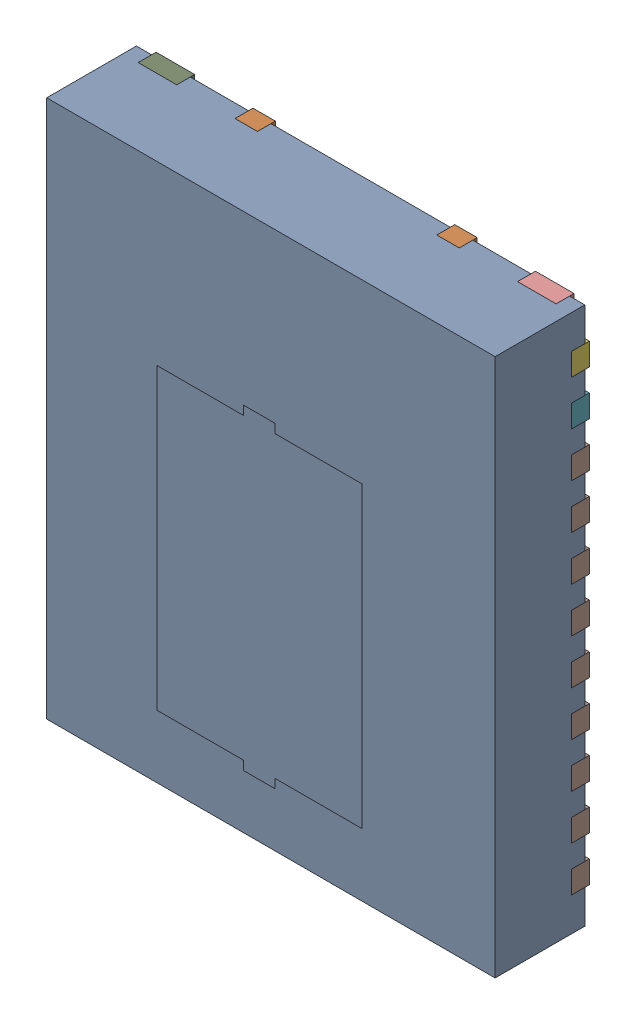
SolidWorks assembly DMM0022A, configuration Default. Lengths in mm.
Overall size (5 6 1.05).
14 component instances, 13 part files, 0 mates.
Components (placement in the parent):
- BODY-SON-1: BODY-SON [Default] at (0 0 0.05) x (1 0 0) z (0 -1 0) size (5 1 6)
- FRAME-DMM0022A-1: FRAME-DMM0022A [Default] x (1 0 0) z (0 -1 0) size (5 0.2 6)
  - Open CASCADE STEP translator 7.5 1.2.1.2.1-1: Open CASCADE STEP translator 7.5 1.2.1.2.1 [Default] at origin size (3.5 0.2 6)
  - Open CASCADE STEP translator 7.5 1.2.1.2.2-1: Open CASCADE STEP translator 7.5 1.2.1.2.2 [Default] at origin size (0.5 0.2 0.25)
  - Open CASCADE STEP translator 7.5 1.2.1.2.3-1: Open CASCADE STEP translator 7.5 1.2.1.2.3 [Default] at origin size (0.5 0.2 0.25)
  - Open CASCADE STEP translator 7.5 1.2.1.2.4-1: Open CASCADE STEP translator 7.5 1.2.1.2.4 [Default] at origin size (0.5 0.2 4.25)
  - Open CASCADE STEP translator 7.5 1.2.1.2.5-1: Open CASCADE STEP translator 7.5 1.2.1.2.5 [Default] at origin size (0.5 0.2 0.25)
  - Open CASCADE STEP translator 7.5 1.2.1.2.6-1: Open CASCADE STEP translator 7.5 1.2.1.2.6 [Default] at origin size (0.5 0.2 0.25)
  - Open CASCADE STEP translator 7.5 1.2.1.2.7-1: Open CASCADE STEP translator 7.5 1.2.1.2.7 [Default] at origin size (0.5 0.2 4.25)
  - Open CASCADE STEP translator 7.5 1.2.1.2.8-1: Open CASCADE STEP translator 7.5 1.2.1.2.8 [Default] at origin size (0.43 0.2 0.18)
  - Open CASCADE STEP translator 7.5 1.2.1.2.9-1: Open CASCADE STEP translator 7.5 1.2.1.2.9 [Default] at origin size (0.43 0.2 0.18)
  - Open CASCADE STEP translator 7.5 1.2.1.2.10-1: Open CASCADE STEP translator 7.5 1.2.1.2.10 [Default] at origin size (0.43 0.2 0.18)
  - Open CASCADE STEP translator 7.5 1.2.1.2.11-1: Open CASCADE STEP translator 7.5 1.2.1.2.11 [Default] at origin size (0.43 0.2 0.18)
- HEATSLUG-1: HEATSLUG [Default] at (-0.128 -0.635 0.958) x (1 0 0) z (0 -1 0) size (2.28 0.09 3.53)
